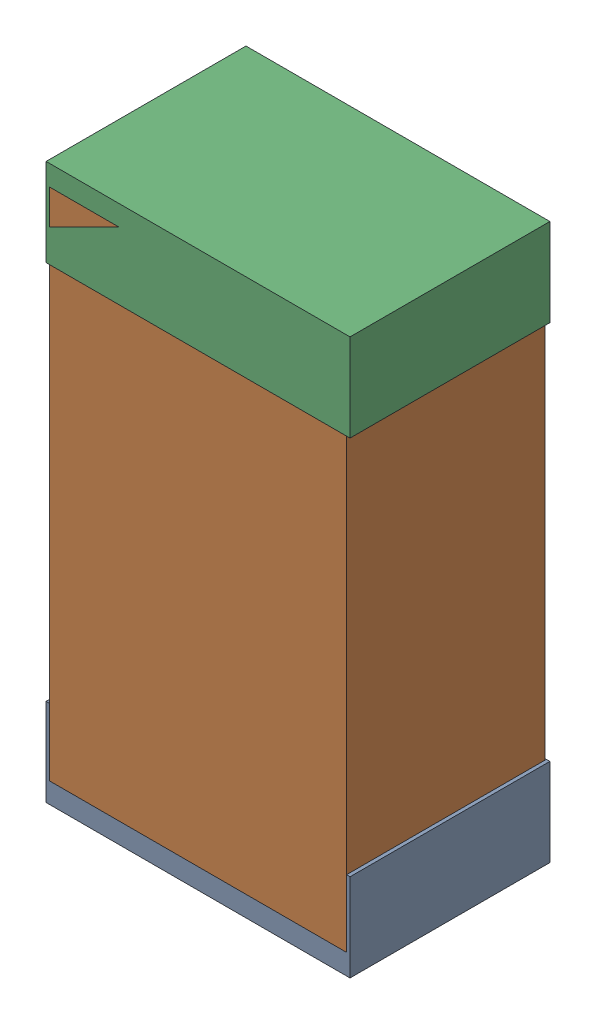
SolidWorks assembly R34Kanaloa_v2.0.0_Motor, configuration Default. Lengths in mm.
Overall size (1.3 2.38 0.85).
6 component instances, 2 part files, 0 mates.
Components (placement in the parent):
- 330415056-1: 330415056 [Default] at (41.402 123.968 -1.9574) size (1.3 0.38 0.85)
  - Extruded_2-1: Extruded_2 [Default] at origin size (1.3 0.38 0.85)
- 334787376-1: 334787376 [Default] at (41.402 124.968 -1.9524) size (1.27 2.2 0.85)
  - Extruded_16-1: Extruded_16 [Default] at origin size (1.27 2.2 0.85)
- 330415056-2: 330415056 [Default] at (41.402 125.968 -1.9574) size (1.3 0.38 0.85)
  - Extruded_2-1: Extruded_2 [Default] at origin size (1.3 0.38 0.85)
